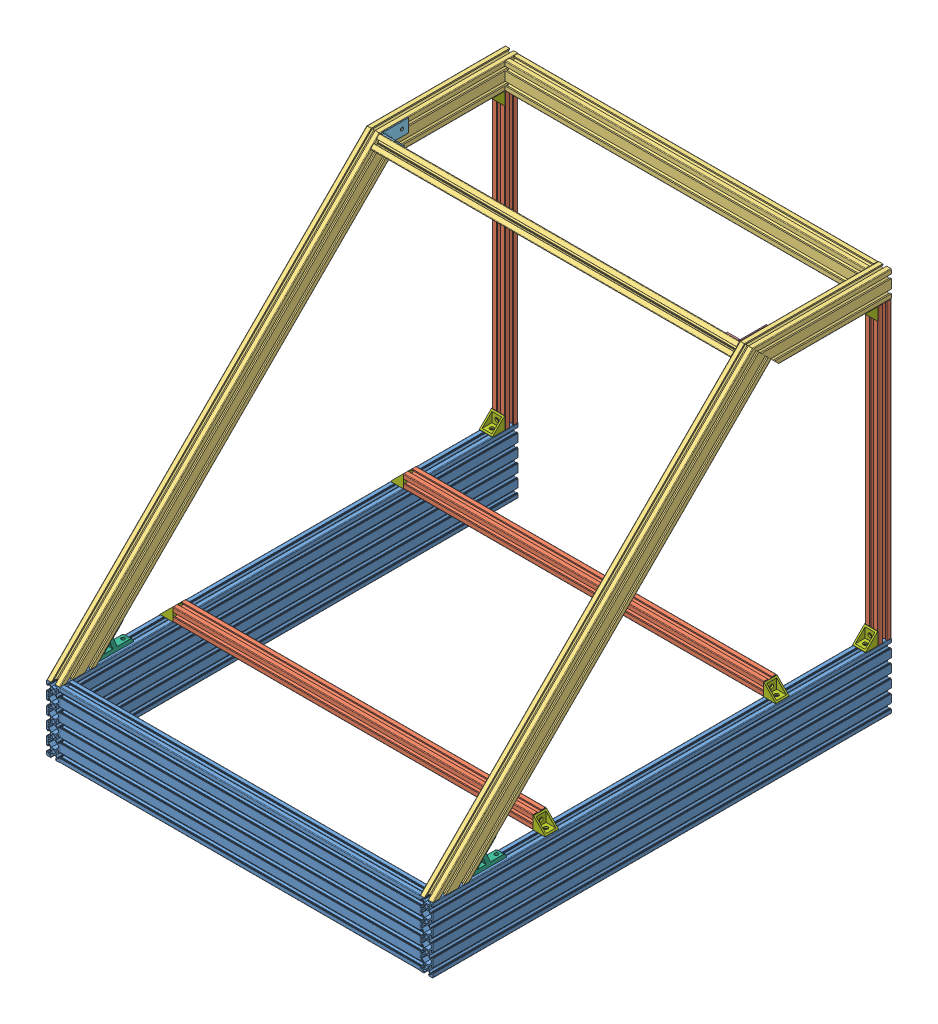
SolidWorks assembly printer-frame, configuration Default. Lengths in mm.
Overall size (590 588.79 700).
33 component instances, 8 part files, 90 mates.
Components (placement in the parent):
- 20100-extrusion-1: 20100-extrusion [700] x (0 -1 0) z (0 0 1) size (100 20 700)
- 20100-extrusion-2: 20100-extrusion [700] at (-570 0 0) x (0 -1 0) z (0 0 1) size (100 20 700)
- 20100-extrusion-3: 20100-extrusion [550] at (-285 0 340) x (0 -1 0) z (1 0 0) size (100 20 550)
- 2020-extrusion-1: 2020-extrusion [550] at (-285 30 -184.814) x (0 0 -1) z (1 0 0) size (20 20 550)
- 2020-extrusion-3: 2020-extrusion [550] at (-285 30 167.3507) x (0 -1 0) z (1 0 0) size (20 20 550)
- 2040-extrusion-1: 2040-extrusion [691] at (0 674.4273 -332.7116) x (-1 0 0) z (0 0.707107 -0.707107) size (20 40 691)
- 2040-extrusion-2: 2040-extrusion [691] at (-570 674.4273 -332.7116) x (-1 0 0) z (0 0.707107 -0.707107) size (20 40 691)
- 2040-extrusion-3: 2040-extrusion [550] at (315 487.3976 -145.6819) x (0 0.707107 -0.707107) z (1 0 0) size (20 40 550)
- 2040-extrusion-4: 2040-extrusion [blower-segment] at (-570 488.6108 -844.3058) x (-1 0 0) z (0 0 -1) size (20 40 211.39)
- 2040-extrusion-5: 2040-extrusion [blower-segment] at (0 488.6108 -844.3058) x (-1 0 0) z (0 0 -1) size (20 40 211.39)
- angled-alu-bracket-1: angled-alu-bracket [Default] at (-11.6 498.6108 -165.8735) x (0 0 1) z (0 -1 0) size (41.31 21.77 20.17)
- angled-alu-bracket-mirrored-1: angled-alu-bracket-mirrored [Default] at (-561.6 498.6108 -165.8735) x (0 0 1) z (0 -1 0) size (41.31 21.77 20.17)
- 2020-extrusion-4: 2020-extrusion [448.61] at (0 244.305 -340) x (0 0 -1) z (0 -1 0) size (20 20 448.61)
- 2020-extrusion-5: 2020-extrusion [448.61] at (-570 244.305 -340) x (0 0 -1) z (0 -1 0) size (20 20 448.61)
- 2040-extrusion-6: 2040-extrusion [550] at (315 488.6108 -340.0008) x (0 0 -1) z (1 0 0) size (20 40 550)
- frame-angled-support-1: frame-angled-support [Default] at (-6 20 293.4315) size (12 42.43 58.59)
- frame-angled-support-2: frame-angled-support [Default] at (-576 20 293.4315) size (12 42.43 58.59)
- 2020-angle-bracket-1: 2020-angle-bracket [Default] at (0 20 -320) x (0 0 -1) z (1 0 0) size (19.29 19.29 20)
- 2020-angle-bracket-2: 2020-angle-bracket [Default] at (-570 20 -320) x (0 0 -1) z (1 0 0) size (19.29 19.29 20)
- 2020-angle-bracket-3: 2020-angle-bracket [Default] at (-570 20 -184.814) size (19.29 19.29 20)
- 2020-angle-bracket-4: 2020-angle-bracket [Default] at (0 20 -184.814) x (-1 0 0) z (0 0 -1) size (19.29 19.29 20)
- 2020-angle-bracket-5: 2020-angle-bracket [Default] at (0 20 167.3507) x (-1 0 0) z (0 0 -1) size (19.29 19.29 20)
- 2020-angle-bracket-6: 2020-angle-bracket [Default] at (-570 20 167.3507) size (19.29 19.29 20)
- 2020-angle-bracket-7: 2020-angle-bracket [Default] at (-570 458.6108 -330) x (0 1 0) z (1 0 0) size (19.29 19.29 20)
- 2020-angle-bracket-8: 2020-angle-bracket [Default] at (0 458.6108 -330) x (0 1 0) z (1 0 0) size (19.29 19.29 20)
- m6-buttonhead-screw-1: m6-buttonhead-screw [20] at (-8 10 340) x (0 -1 0) z (0 0 1) size (10.2 23.2 10.2)
- m6-buttonhead-screw-2: m6-buttonhead-screw [20] at (-8 -70 340) x (0 -1 0) z (0 0 1) size (10.2 23.2 10.2)
- m6-buttonhead-screw-3: m6-buttonhead-screw [20] at (-562 10 340) x (0 -0.377608 0.925966) z (0 -0.925966 -0.377608) size (10.2 23.2 10.2)
- m6-buttonhead-screw-4: m6-buttonhead-screw [20] at (-562 -70 340) x (0 -0.377608 0.925966) z (0 -0.925966 -0.377608) size (10.2 23.2 10.2)
- m6-buttonhead-screw-5: m6-buttonhead-screw [20] at (-562 494.4687 -138.6108) x (0 0.992847 0.119394) z (0 -0.119394 0.992847) size (10.2 23.2 10.2)
- m6-buttonhead-screw-6: m6-buttonhead-screw [20] at (-562 480.3265 -152.7529) x (0 0.992847 0.119394) z (0 -0.119394 0.992847) size (10.2 23.2 10.2)
- m6-buttonhead-screw-7: m6-buttonhead-screw [20] at (-8 494.4687 -138.6108) x (0 -0.268771 0.963204) z (0 0.963204 0.268771) size (10.2 23.2 10.2)
- m6-buttonhead-screw-8: m6-buttonhead-screw [20] at (-8 480.3265 -152.7529) x (0 -0.268771 0.963204) z (0 0.963204 0.268771) size (10.2 23.2 10.2)
Mates (geometry in assembly coordinates):
- Coincident2: coincident: point of 20100-extrusion-1
- Coincident3: coincident aligned: plane of 20100-extrusion-1 through (0 0 0) normal (0 0 1)
- Coincident4: coincident anti-aligned: plane of 20100-extrusion-1 through (0 0 0) normal (0 -1 0)
- Coincident5: coincident aligned: plane of 20100-extrusion-1 through (0 0 0) normal (1 0 0)
- Coincident13: coincident anti-aligned: plane of 20100-extrusion-1 through (-3.9 20 350) normal (0 1 0); plane of 2020-extrusion-1 through (-10 20 -174.814) normal (0 -1 0)
- Coincident14: coincident anti-aligned: plane of 20100-extrusion-1 through (-10 -6.1 350) normal (-1 0 0); plane of 2020-extrusion-1 through (-10 30 -184.814) normal (1 0 0)
- Coincident21: coincident anti-aligned: plane of 20100-extrusion-1 through (-10 -6.1 350) normal (-1 0 0); plane of 20100-extrusion-3 through (-10 0 340) normal (1 0 0)
- Coincident22: coincident aligned: plane of 20100-extrusion-1 through (0 0 350) normal (0 0 1); plane of 20100-extrusion-3 through (-10 -6.1 350) normal (0 0 1)
- Coincident23: coincident anti-aligned: plane of 20100-extrusion-2 through (-560 20 350) normal (1 0 0); plane of 20100-extrusion-3 through (-560 0 340) normal (-1 0 0)
- Coincident25: coincident aligned: plane of 20100-extrusion-2 through (-566.1 20 350) normal (0 1 0); plane of 20100-extrusion-3 through (-10 20 343.9) normal (0 1 0)
- Coincident26: coincident aligned: plane of 20100-extrusion-2 through (-570 0 350) normal (0 0 1); plane of 20100-extrusion-3 through (-10 20 350) normal (0 0 1)
- Coincident27: coincident aligned: plane of 20100-extrusion-1 through (-3.9 20 350) normal (0 1 0); plane of 20100-extrusion-3 through (-10 20 336.1) normal (0 1 0)
- Coincident28: coincident aligned: plane of 2020-extrusion-1 through (-10 30 -184.814) normal (1 0 0); plane of 2020-extrusion-3 through (-10 30 167.3507) normal (1 0 0)
- Coincident29: coincident aligned: plane of 2020-extrusion-1 through (-10 40 -174.814) normal (0 1 0); plane of 2020-extrusion-3 through (-10 40 157.3507) normal (0 1 0)
- Coincident30: coincident anti-aligned: plane of 20100-extrusion-1 through (3.9 20 350) normal (0 1 0); plane of 2040-extrusion-1 through (-10 20 350) normal (0 -1 0)
- Coincident31: coincident aligned: plane of 20100-extrusion-1 through (10 20 350) normal (1 0 0); plane of 2040-extrusion-1 through (10 489.5189 -157.7027) normal (1 0 0)
- Coincident32: coincident aligned: line of 20100-extrusion-1 through (-3.9 20 350) axis (-1 0 0); line of 2040-extrusion-1 through (-3 20 350) axis (-1 0 0)
- Coincident33: coincident anti-aligned: plane of 20100-extrusion-2 through (-573.9 20 350) normal (0 1 0); plane of 2040-extrusion-2 through (-580 20 350) normal (0 -1 0)
- Coincident34: coincident aligned: plane of 20100-extrusion-2 through (-580 20 350) normal (-1 0 0); plane of 2040-extrusion-2 through (-580 507.9037 -139.3179) normal (-1 0 0)
- Coincident35: coincident aligned: line of 20100-extrusion-2 through (-573.9 20 350) axis (-1 0 0); line of 2040-extrusion-2 through (-573 20 350) axis (-1 0 0)
- Coincident36: coincident anti-aligned: plane of 2040-extrusion-2 through (-560 489.5189 -157.7027) normal (1 0 0); plane of 2040-extrusion-3 through (-560 491.5316 -136.5981) normal (-1 0 0)
- Coincident37: coincident aligned: plane of 2040-extrusion-2 through (-561 508.6108 -138.6108) normal (0 0.707107 0.707107); plane of 2040-extrusion-3 through (-10 503.661 -133.661) normal (0 0.707107 0.707107)
- Coincident38: coincident aligned: plane of 2040-extrusion-2 through (-566.5 501.0776 -146.144) normal (0 0.707107 -0.707107); plane of 2040-extrusion-3 through (-10 499.4184 -147.8032) normal (0 0.707107 -0.707107)
- Coincident39: coincident anti-aligned: plane of 2040-extrusion-2 through (-566.5 501.0776 -146.144) normal (0 0.707107 -0.707107); plane of 2040-extrusion-4 through (-580 508.6108 -138.6108) normal (0 -0.707107 0.707107)
- Coincident40: coincident: line of 2040-extrusion-2 through (-573 508.6108 -138.6108) axis (-1 0 0); plane of 2040-extrusion-4 through (-573 508.6108 -350.0008) normal (0 1 0)
- Coincident41: coincident aligned: plane of 2040-extrusion-2 through (-580 507.9037 -139.3179) normal (-1 0 0); plane of 2040-extrusion-4 through (-580 507.6108 -350.0008) normal (-1 0 0)
- Coincident42: coincident: line of 2040-extrusion-1 through (9 508.6108 -138.6108) axis (-1 0 0); plane of 2040-extrusion-5 through (-10 508.6108 -138.6108) normal (0 -0.707107 0.707107)
- Coincident43: coincident aligned: plane of 2040-extrusion-1 through (10 503.661 -143.5605) normal (1 0 0); plane of 2040-extrusion-5 through (10 501.6108 -350.0008) normal (1 0 0)
- Coincident44: coincident: line of 2040-extrusion-1 through (-3 508.6108 -138.6108) axis (-1 0 0); plane of 2040-extrusion-5 through (-3 508.6108 -350.0008) normal (0 1 0)
- Coincident45: coincident anti-aligned: plane of 2040-extrusion-5 through (-10 495.6108 -350.0008) normal (-1 0 0); plane of angled-alu-bracket-1 through (-10 498.6108 -165.8735) normal (1 0 0)
- Coincident46: coincident anti-aligned: plane of 2040-extrusion-3 through (-10 499.4184 -147.8032) normal (0 0.707107 -0.707107); plane of angled-alu-bracket-1 through (-11.6 489.9794 -157.2422) normal (0 -0.707107 0.707107)
- Coincident47: coincident aligned: plane of 2040-extrusion-5 through (-3 508.6108 -350.0008) normal (0 1 0); plane of angled-alu-bracket-1 through (-10 508.6108 -180.8735) normal (0 1 0)
- Coincident48: coincident anti-aligned: plane of 2040-extrusion-4 through (-560 501.6108 -350.0008) normal (1 0 0); plane of angled-alu-bracket-mirrored-1 through (-560 498.6108 -165.8735) normal (-1 0 0)
- Coincident50: coincident anti-aligned: plane of 2040-extrusion-3 through (-10 499.4184 -147.8032) normal (0 0.707107 -0.707107); plane of angled-alu-bracket-mirrored-1 through (-558.4 489.9794 -157.2422) normal (0 -0.707107 0.707107)
- Coincident51: coincident aligned: plane of 2040-extrusion-4 through (-561 508.6108 -350.0008) normal (0 1 0); plane of angled-alu-bracket-mirrored-1 through (-560 508.6108 -180.8735) normal (0 1 0)
- Coincident52: coincident anti-aligned: plane of 20100-extrusion-1 through (-3.9 20 350) normal (0 1 0); plane of 2020-extrusion-4 through (0 20 -340) normal (0 -1 0)
- Coincident53: coincident aligned: plane of 20100-extrusion-1 through (10 20 350) normal (1 0 0); plane of 2020-extrusion-4 through (10 20 -343.1) normal (1 0 0)
- Coincident54: coincident aligned: plane of 20100-extrusion-1 through (0 0 -350) normal (0 0 -1); plane of 2020-extrusion-4 through (10 20 -350) normal (0 0 -1)
- Coincident55: coincident anti-aligned: plane of 20100-extrusion-2 through (-566.1 20 350) normal (0 1 0); plane of 2020-extrusion-5 through (-570 20 -340) normal (0 -1 0)
- Coincident56: coincident aligned: plane of 20100-extrusion-2 through (-560 20 350) normal (1 0 0); plane of 2020-extrusion-5 through (-560 20 -343.1) normal (1 0 0)
- Coincident57: coincident aligned: plane of 20100-extrusion-2 through (-570 0 -350) normal (0 0 -1); plane of 2020-extrusion-5 through (-560 20 -350) normal (0 0 -1)
- Coincident58: coincident aligned: plane of 2040-extrusion-5 through (3.5 497.9572 -350.0008) normal (0 0 -1); plane of 2040-extrusion-6 through (-10 495.6108 -350.0008) normal (0 0 -1)
- Coincident59: coincident anti-aligned: plane of 2040-extrusion-5 through (-10 507.6108 -350.0008) normal (-1 0 0); plane of 2040-extrusion-6 through (-10 497.9572 -336.5008) normal (1 0 0)
- Coincident60: coincident aligned: plane of 2040-extrusion-5 through (-3 508.6108 -350.0008) normal (0 1 0); plane of 2040-extrusion-6 through (-10 508.6108 -343.0008) normal (0 1 0)
- Coincident61: coincident anti-aligned: plane of 20100-extrusion-1 through (3.9 20 350) normal (0 1 0); plane of frame-angled-support-1 through (6 20 293.4315) normal (0 -1 0)
- Coincident62: coincident anti-aligned: plane of 2040-extrusion-1 through (3 480.3265 -166.8951) normal (0 -0.707107 -0.707107); plane of frame-angled-support-1 through (6 20 293.4315) normal (0 0.707107 0.707107)
- Width2: width aligned: plane of frame-angled-support-1 through (6 20 293.4315) normal (1 0 0); plane of 2040-extrusion-1 through (-6 20 293.4315) normal (-1 0 0); plane of frame-angled-support-1 through (10 489.5189 -157.7027) normal (1 0 0); plane of 2040-extrusion-1 through (-10 499.4184 -147.8032) normal (-1 0 0)
- Coincident63: coincident anti-aligned: plane of 20100-extrusion-2 through (-573.9 20 350) normal (0 1 0); plane of frame-angled-support-2 through (-564 20 293.4315) normal (0 -1 0)
- Coincident64: coincident anti-aligned: plane of 2040-extrusion-2 through (-579 480.3265 -166.8951) normal (0 -0.707107 -0.707107); plane of frame-angled-support-2 through (-564 20 293.4315) normal (0 0.707107 0.707107)
- Width3: width anti-aligned: plane of frame-angled-support-2 through (-576 20 293.4315) normal (-1 0 0); plane of 2040-extrusion-2 through (-564 20 293.4315) normal (1 0 0); plane of frame-angled-support-2 through (-560 489.5189 -157.7027) normal (1 0 0); plane of 2040-extrusion-2 through (-580 499.4184 -147.8032) normal (-1 0 0)
- Coincident65: coincident anti-aligned: plane of 2020-extrusion-4 through (-3.1 20 -330) normal (0 0 1); plane of 2020-angle-bracket-1 through (-10 40 -330) normal (0 0 -1)
- Coincident66: coincident anti-aligned: plane of 20100-extrusion-1 through (-3.9 20 350) normal (0 1 0); plane of 2020-angle-bracket-1 through (0 20 -320) normal (0 -1 0)
- Coincident67: coincident aligned: plane of 2020-extrusion-4 through (10 20 -330) normal (1 0 0); plane of 2020-angle-bracket-1 through (10 40 -310) normal (1 0 0)
- Coincident68: coincident aligned: plane of 2020-extrusion-5 through (-560 20 -330) normal (1 0 0); plane of 2020-angle-bracket-2 through (-560 40 -310) normal (1 0 0)
- Coincident69: coincident anti-aligned: plane of 2020-extrusion-5 through (-573.1 20 -330) normal (0 0 1); plane of 2020-angle-bracket-2 through (-580 40 -330) normal (0 0 -1)
- Coincident70: coincident anti-aligned: plane of 20100-extrusion-2 through (-573.9 20 350) normal (0 1 0); plane of 2020-angle-bracket-2 through (-570 20 -320) normal (0 -1 0)
- Coincident71: coincident aligned: plane of 2020-extrusion-1 through (-10 40 -194.814) normal (0 0 -1); plane of 2020-angle-bracket-3 through (-580 40 -194.814) normal (0 0 -1)
- Coincident72: coincident anti-aligned: plane of 2020-extrusion-1 through (-560 30 -184.814) normal (-1 0 0); plane of 2020-angle-bracket-3 through (-560 40 -194.814) normal (1 0 0)
- Coincident73: coincident anti-aligned: plane of 20100-extrusion-2 through (-566.1 20 350) normal (0 1 0); plane of 2020-angle-bracket-3 through (-570 20 -184.814) normal (0 -1 0)
- Symmetric1: symmetric anti-aligned: plane of 2020-extrusion-1 through (-10 30 -184.814) normal (1 0 0); plane of 2020-angle-bracket-3 through (-10 40 -174.814) normal (-1 0 0); plane of 2020-angle-bracket-4 through (-580 40 -194.814) normal (0 0 -1)
- Coincident74: coincident anti-aligned: plane of 20100-extrusion-1 through (-3.9 20 350) normal (0 1 0); plane of 2020-angle-bracket-4 through (0 20 -184.814) normal (0 -1 0)
- Coincident75: coincident aligned: plane of 2020-extrusion-1 through (-10 40 -194.814) normal (0 0 -1); plane of 2020-angle-bracket-4 through (10 40 -194.814) normal (0 0 -1)
- Coincident76: coincident anti-aligned: plane of 2020-extrusion-3 through (-10 30 167.3507) normal (1 0 0); plane of 2020-angle-bracket-5 through (-10 40 177.3507) normal (-1 0 0)
- Coincident77: coincident aligned: plane of 2020-extrusion-3 through (-10 40 177.3507) normal (0 0 1); plane of 2020-angle-bracket-5 through (10 40 177.3507) normal (0 0 1)
- Coincident78: coincident anti-aligned: plane of 20100-extrusion-1 through (-3.9 20 350) normal (0 1 0); plane of 2020-angle-bracket-5 through (0 20 167.3507) normal (0 -1 0)
- Coincident79: coincident anti-aligned: plane of 2020-extrusion-3 through (-560 30 167.3507) normal (-1 0 0); plane of 2020-angle-bracket-6 through (-560 40 157.3507) normal (1 0 0)
- Coincident80: coincident anti-aligned: plane of 20100-extrusion-2 through (-566.1 20 350) normal (0 1 0); plane of 2020-angle-bracket-6 through (-570 20 167.3507) normal (0 -1 0)
- Coincident81: coincident aligned: plane of 2020-extrusion-3 through (-10 40 177.3507) normal (0 0 1); plane of 2020-angle-bracket-6 through (-580 40 177.3507) normal (0 0 1)
- Coincident82: coincident anti-aligned: plane of 2040-extrusion-4 through (-579 468.6108 -350.0008) normal (0 -1 0); plane of 2020-angle-bracket-7 through (-580 468.6108 -310) normal (0 1 0)
- Coincident83: coincident anti-aligned: plane of 2020-extrusion-5 through (-573.1 20 -330) normal (0 0 1); plane of 2020-angle-bracket-7 through (-570 458.6108 -330) normal (0 0 -1)
- Coincident84: coincident aligned: plane of 2040-extrusion-4 through (-580 475.6108 -350.0008) normal (-1 0 0); plane of 2020-angle-bracket-7 through (-580 448.6108 -310) normal (-1 0 0)
- Coincident85: coincident aligned: plane of 2040-extrusion-5 through (10 469.6108 -350.0008) normal (1 0 0); plane of 2020-angle-bracket-8 through (10 448.6108 -310) normal (1 0 0)
- Coincident86: coincident anti-aligned: plane of 2040-extrusion-5 through (3 468.6108 -350.0008) normal (0 -1 0); plane of 2020-angle-bracket-8 through (-10 468.6108 -310) normal (0 1 0)
- Coincident87: coincident anti-aligned: plane of 2020-extrusion-4 through (10 20 -330) normal (0 0 1); plane of 2020-angle-bracket-8 through (0 458.6108 -330) normal (0 0 -1)
- Concentric1: concentric anti-aligned: cylinder of 20100-extrusion-3 through (-10 10 340) axis (-1 0 0) radius 2.5; cylinder of m6-buttonhead-screw-1 through (-28 10 340) axis (1 0 0) radius 3
- Coincident88: coincident anti-aligned: plane of 20100-extrusion-1 through (-8 6.9 350) normal (1 0 0); plane of m6-buttonhead-screw-1 through (-8 10 340) normal (-1 0 0)
- Concentric2: concentric anti-aligned: cylinder of 20100-extrusion-3 through (-10 -70 340) axis (-1 0 0) radius 2.5; cylinder of m6-buttonhead-screw-2 through (-28 -70 340) axis (1 0 0) radius 3
- Coincident89: coincident anti-aligned: plane of 20100-extrusion-1 through (-8 -73.1 350) normal (1 0 0); plane of m6-buttonhead-screw-2 through (-8 -70 340) normal (-1 0 0)
- Concentric3: concentric aligned: cylinder of 20100-extrusion-3 through (-10 10 340) axis (-1 0 0) radius 2.5; cylinder of m6-buttonhead-screw-3 through (-542 10 340) axis (-1 0 0) radius 3
- Coincident90: coincident anti-aligned: plane of 20100-extrusion-2 through (-562 13.1 350) normal (-1 0 0); plane of m6-buttonhead-screw-3 through (-562 10 340) normal (1 0 0)
- Concentric4: concentric aligned: cylinder of 20100-extrusion-3 through (-10 -70 340) axis (-1 0 0) radius 2.5; cylinder of m6-buttonhead-screw-4 through (-542 -70 340) axis (-1 0 0) radius 3
- Coincident91: coincident anti-aligned: plane of 20100-extrusion-2 through (-562 -66.9 350) normal (-1 0 0); plane of m6-buttonhead-screw-4 through (-562 -70 340) normal (1 0 0)
- Concentric5: concentric aligned: cylinder of 2040-extrusion-3 through (-10 494.4687 -138.6108) axis (-1 0 0) radius 2.5; cylinder of m6-buttonhead-screw-5 through (-542 494.4687 -138.6108) axis (-1 0 0) radius 3
- Coincident92: coincident anti-aligned: plane of 2040-extrusion-2 through (-562 505.7824 -141.4392) normal (-1 0 0); plane of m6-buttonhead-screw-5 through (-562 494.4687 -138.6108) normal (1 0 0)
- Concentric6: concentric aligned: cylinder of 2040-extrusion-3 through (-10 480.3265 -152.7529) axis (-1 0 0) radius 2.5; cylinder of m6-buttonhead-screw-6 through (-542 480.3265 -152.7529) axis (-1 0 0) radius 3
- Coincident93: coincident anti-aligned: plane of 2040-extrusion-2 through (-562 491.6402 -155.5813) normal (-1 0 0); plane of m6-buttonhead-screw-6 through (-562 480.3265 -152.7529) normal (1 0 0)
- Concentric7: concentric anti-aligned: cylinder of 2040-extrusion-3 through (-10 494.4687 -138.6108) axis (-1 0 0) radius 2.5; cylinder of m6-buttonhead-screw-7 through (-28 494.4687 -138.6108) axis (1 0 0) radius 3
- Coincident95: coincident anti-aligned: plane of 2040-extrusion-1 through (-8 503.661 -143.5605) normal (1 0 0); plane of m6-buttonhead-screw-7 through (-8 494.4687 -138.6108) normal (-1 0 0)
- Concentric8: concentric anti-aligned: cylinder of 2040-extrusion-3 through (-10 480.3265 -152.7529) axis (-1 0 0) radius 2.5; cylinder of m6-buttonhead-screw-8 through (-28 480.3265 -152.7529) axis (1 0 0) radius 3
- Coincident96: coincident anti-aligned: plane of 2040-extrusion-1 through (-8 489.5189 -157.7027) normal (1 0 0); plane of m6-buttonhead-screw-8 through (-8 480.3265 -152.7529) normal (-1 0 0)
